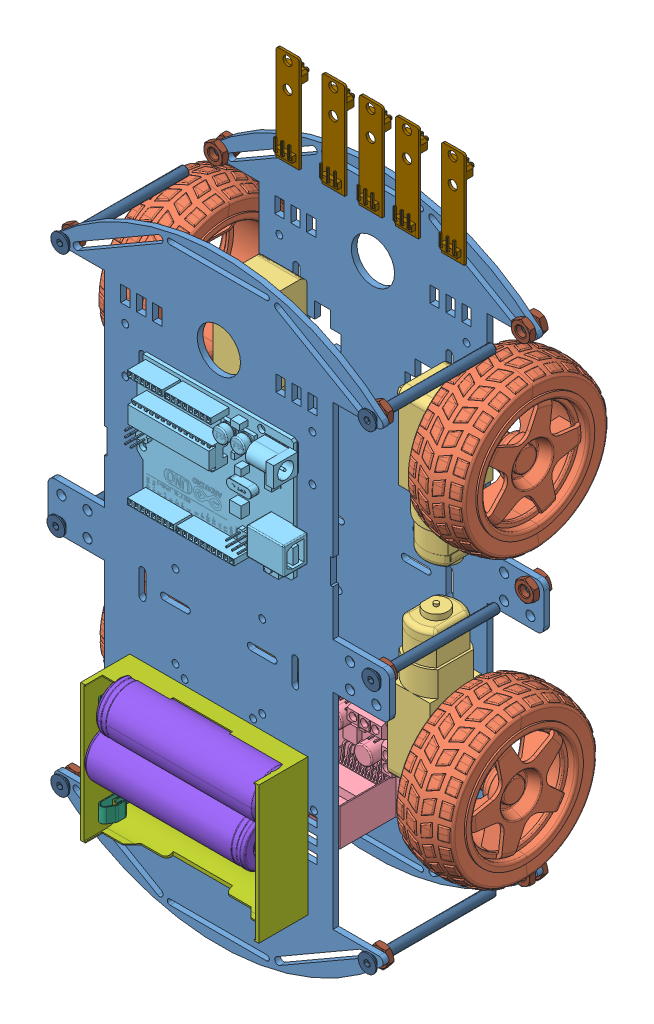
SolidWorks assembly Assem1, configuration Default. Lengths in mm.
Overall size (160.5 287.1 118.28).
55 component instances, 11 part files, 95 mates.
Components (placement in the parent):
- Chassis-1: Chassis [Défaut] at (34.1523 63.1715 225.3046) size (149.66 262 2.5)
- ensemble roue-1: ensemble roue [Default] at (48.6677 124.5638 247.2809) x (0 0.999098 -0.042468) z (-1 0 0) size (89.53 69.08 58.2)
  - Wheel D65x25-1: Wheel D65x25 [Default] at (-64.7956 10.9879 41.7655) size (69.1 69.08 30)
  - Arduino Gear Motor-1: Arduino Gear Motor [Default] at (-75.7856 11.455 2.1655) x (0 0 1) z (-0.999098 0.042468 0) size (37.2 22.5 65.5)
- ensemble roue-2: ensemble roue [Default] at (120.1368 124.5638 230.8284) x (0 0.999098 0.042468) z (1 0 0) size (89.53 69.08 58.2)
  - Wheel D65x25-1: Wheel D65x25 [Default] at (-64.7956 10.9879 41.7655) size (69.1 69.08 30)
  - Arduino Gear Motor-1: Arduino Gear Motor [Default] at (-75.7856 11.455 2.1655) x (0 0 1) z (-0.999098 0.042468 0) size (37.2 22.5 65.5)
- ensemble roue-4: ensemble roue [Default] at (48.1677 122.1564 230.8284) x (0 -0.999098 0.042468) z (-1 0 0) size (89.53 69.08 58.2)
  - Wheel D65x25-1: Wheel D65x25 [Default] at (-64.7956 10.9879 41.7655) size (69.1 69.08 30)
  - Arduino Gear Motor-1: Arduino Gear Motor [Default] at (-75.7856 11.455 2.1655) x (0 0 1) z (-0.999098 0.042468 0) size (37.2 22.5 65.5)
- ensemble roue-5: ensemble roue [Default] at (125.1368 122.1564 247.2809) x (0 -0.999098 -0.042468) z (1 0 0) size (89.53 69.08 58.2)
  - Wheel D65x25-1: Wheel D65x25 [Default] at (-64.7956 10.9879 41.7655) size (69.1 69.08 30)
  - Arduino Gear Motor-1: Arduino Gear Motor [Default] at (-75.7856 11.455 2.1655) x (0 0 1) z (-0.999098 0.042468 0) size (37.2 22.5 65.5)
- L298N Motor Driver-1: L298N Motor Driver [Default] at (84.1523 35.5001 227.8046) x (1 0 0) z (0 -1 0) size (43.5 26 43.5)
- Chassis-2: Chassis [Défaut] at (34.1523 63.1715 292.8046) size (149.66 262 2.5)
- Arduino UNO-1: Arduino UNO [Predeterminado] at (82.8616 175.6554 295.3046) x (-1 0 0) z (0 1 0) size (74.8 15.1 53.3)
- Hold_18650-3p.stp-1: Hold_18650-3p.stp [Default] at (84.1523 53.3601 295.3046) x (0 -1 0) z (0 0 1) size (60 78 25.5)
  - eBom-prt0.stp-1: eBom-prt0.stp [Default] at (-20 -36 0) size (6.4 5.3 21.4)
  - eBom-prt0.stp-2: eBom-prt0.stp [Default] at (-20 36 0) x (-1 0 0) z (0 0 1) size (6.4 5.3 21.4)
  - eBom-prt0.stp-3: eBom-prt0.stp [Default] at (0 -36 0) size (6.4 5.3 21.4)
  - eBom-prt0.stp-4: eBom-prt0.stp [Default] at (0 36 0) x (-1 0 0) z (0 0 1) size (6.4 5.3 21.4)
  - eBom-prt0.stp-5: eBom-prt0.stp [Default] at (20 -36 0) size (6.4 5.3 21.4)
  - eBom-prt0.stp-6: eBom-prt0.stp [Default] at (20 36 0) x (-1 0 0) z (0 0 1) size (6.4 5.3 21.4)
  - eBom-prt1.stp-1: eBom-prt1.stp [Default] at origin size (60 78 21.5)
- 21700_li_battery-1: 21700_li_battery [Default] at (121.6523 73.3601 306.8046) x (0 1 0) z (0 0 1) size (21 70.03 21)
- 21700_li_battery-2: 21700_li_battery [Default] at (46.6523 53.3601 306.8046) x (0 0.381849 -0.924225) z (0 -0.924225 -0.381849) size (21 70.03 21)
- Sensor-1: Sensor [Default] at (120.0976 257.9627 228.8046) x (0 1 0) z (-1 0 0) size (42 9.8 10)
- Sensor-2: Sensor [Default] at (47.7712 257.9627 228.8046) x (0 1 0) z (-1 0 0) size (42 9.8 10)
- socket countersunk head screw_am-14: socket countersunk head screw_am [B18.3.5M - 4 x 0.7 x 55 Socket FCHS  -- 20N] at (151.4798 226.3601 297.7261) x (0 0 -1) z (-0.801739 -0.597675 0) size (55 7.8 7.8)
- socket countersunk head screw_am-15: socket countersunk head screw_am [B18.3.5M - 4 x 0.7 x 55 Socket FCHS  -- 20N] at (16.8248 226.3601 297.7261) x (0 0 -1) z (1 0 0) size (55 7.8 7.8)
- socket countersunk head screw_am-16: socket countersunk head screw_am [B18.3.5M - 4 x 0.7 x 55 Socket FCHS  -- 20N] at (153.1319 128.6487 297.7261) x (0 0 -1) z (1 0 0) size (55 7.8 7.8)
- socket countersunk head screw_am-13: socket countersunk head screw_am [B18.3.5M - 4 x 0.7 x 55 Socket FCHS  -- 20N] at (151.4798 20.3601 297.7261) x (0 0 -1) z (1 0 0) size (55 7.8 7.8)
- socket countersunk head screw_am-17: socket countersunk head screw_am [B18.3.5M - 4 x 0.7 x 55 Socket FCHS  -- 20N] at (16.8248 20.3601 297.7261) x (0 0 -1) z (1 0 0) size (55 7.8 7.8)
- socket countersunk head screw_am-12: socket countersunk head screw_am [B18.3.5M - 4 x 0.7 x 55 Socket FCHS  -- 20N] at (15.1726 118.0715 297.7261) x (0 0 -1) z (1 0 0) size (55 7.8 7.8)
- hex nut jam_am-1: hex nut jam_am [B18.2.4.5M - Hex jam nut,  M5 x 0.8 --D-N] at (151.4798 226.3601 292.8046) size (8 9.24 2.7)
- hex nut jam_am-2: hex nut jam_am [B18.2.4.5M - Hex jam nut,  M5 x 0.8 --D-N] at (151.4798 226.3601 230.5046) size (8 9.24 2.7)
- hex nut jam_am-3: hex nut jam_am [B18.2.4.5M - Hex jam nut,  M5 x 0.8 --D-N] at (151.4798 226.3601 222.6046) x (0.923728 0.383049 0) z (0 0 -1) size (8 9.24 2.7)
- hex nut jam_am-4: hex nut jam_am [B18.2.4.5M - Hex jam nut,  M5 x 0.8 --D-N] at (153.1319 128.6487 290.1046) x (0.923728 0.383049 0) z (0 0 -1) size (8 9.24 2.7)
- hex nut jam_am-5: hex nut jam_am [B18.2.4.5M - Hex jam nut,  M5 x 0.8 --D-N] at (151.4798 20.3601 290.1046) x (0.923728 0.383049 0) z (0 0 -1) size (8 9.24 2.7)
- hex nut jam_am-6: hex nut jam_am [B18.2.4.5M - Hex jam nut,  M5 x 0.8 --D-N] at (16.8248 20.3601 290.1046) x (0.923728 0.383049 0) z (0 0 -1) size (8 9.24 2.7)
- hex nut jam_am-7: hex nut jam_am [B18.2.4.5M - Hex jam nut,  M5 x 0.8 --D-N] at (15.1726 118.0715 290.1046) x (0.923728 0.383049 0) z (0 0 -1) size (8 9.24 2.7)
- hex nut jam_am-8: hex nut jam_am [B18.2.4.5M - Hex jam nut,  M5 x 0.8 --D-N] at (16.8248 226.3601 292.8046) x (0.999998 0.001761 0) z (0 0 1) size (8 9.24 2.7)
- hex nut jam_am-9: hex nut jam_am [B18.2.4.5M - Hex jam nut,  M5 x 0.8 --D-N] at (16.8248 226.3601 230.5046) size (8 9.24 2.7)
- hex nut jam_am-10: hex nut jam_am [B18.2.4.5M - Hex jam nut,  M5 x 0.8 --D-N] at (15.1726 118.0715 230.5046) size (8 9.24 2.7)
- hex nut jam_am-11: hex nut jam_am [B18.2.4.5M - Hex jam nut,  M5 x 0.8 --D-N] at (16.8248 20.3601 230.5046) size (8 9.24 2.7)
- hex nut jam_am-12: hex nut jam_am [B18.2.4.5M - Hex jam nut,  M5 x 0.8 --D-N] at (16.8248 20.3601 222.6046) x (0.923728 0.383049 0) z (0 0 -1) size (8 9.24 2.7)
- hex nut jam_am-13: hex nut jam_am [B18.2.4.5M - Hex jam nut,  M5 x 0.8 --D-N] at (15.1726 118.0715 222.6046) x (0.923728 0.383049 0) z (0 0 -1) size (8 9.24 2.7)
- hex nut jam_am-14: hex nut jam_am [B18.2.4.5M - Hex jam nut,  M5 x 0.8 --D-N] at (16.8248 226.3601 222.6046) x (0.923728 0.383049 0) z (0 0 -1) size (8 9.24 2.7)
- hex nut jam_am-15: hex nut jam_am [B18.2.4.5M - Hex jam nut,  M5 x 0.8 --D-N] at (153.1319 128.6487 222.6046) x (0.923728 0.383049 0) z (0 0 -1) size (8 9.24 2.7)
- hex nut jam_am-16: hex nut jam_am [B18.2.4.5M - Hex jam nut,  M5 x 0.8 --D-N] at (151.4798 20.3601 222.6046) x (0.923728 0.383049 0) z (0 0 -1) size (8 9.24 2.7)
- hex nut jam_am-17: hex nut jam_am [B18.2.4.5M - Hex jam nut,  M5 x 0.8 --D-N] at (151.4798 20.3601 230.5046) size (8 9.24 2.7)
- hex nut jam_am-18: hex nut jam_am [B18.2.4.5M - Hex jam nut,  M5 x 0.8 --D-N] at (153.1319 128.6487 230.5046) size (8 9.24 2.7)
- Sensor-3: Sensor [Default] at (100.0976 257.9627 228.8046) x (0 1 0) z (-1 0 0) size (42 9.8 10)
- Sensor-4: Sensor [Default] at (67.7712 257.9627 228.8046) x (0 1 0) z (-1 0 0) size (42 9.8 10)
- Sensor-5: Sensor [Default] at (84.1523 257.9627 228.8046) x (0 1 0) z (-1 0 0) size (42 9.8 10)
Mates (geometry in assembly coordinates):
- Coincident1: coincident anti-aligned: plane of Chassis-1 through (154.1465 21.3601 227.8046) normal (0 0 1); plane of ensemble roue-1/Arduino Gear Motor-1 through (55.8523 48.3601 227.8046) normal (0 0 -1)
- Parallel1: parallel anti-aligned: plane of Chassis-1 through (34.1523 23.3601 227.8046) normal (-1 0 0); plane of ensemble roue-1/Arduino Gear Motor-1 through (55.8523 48.3601 250.3046) normal (1 0 0)
- Distance1: distance = 3 mm aligned: plane of ensemble roue-1/Arduino Gear Motor-1 through (37.1523 48.3601 227.8046) normal (-1 0 0); plane of Chassis-1 through (34.1523 23.3601 227.8046) normal (-1 0 0)
- Distance5: distance = 25 mm anti-aligned: plane of ensemble roue-1/Arduino Gear Motor-1 through (46.5023 48.3601 239.0546) normal (0 -1 0); plane of Chassis-1 through (34.1523 23.3601 227.8046) normal (0 1 0)
- Coincident6: coincident anti-aligned: plane of Chassis-1 through (154.1465 21.3601 227.8046) normal (0 0 1); plane of ensemble roue-4/Arduino Gear Motor-1 through (36.6523 198.3601 227.8046) normal (0 0 -1)
- Distance3: distance = 2.5 mm aligned: plane of ensemble roue-4/Arduino Gear Motor-1 through (36.6523 198.3601 250.3046) normal (-1 0 0); plane of Chassis-1 through (34.1523 133.3601 227.8046) normal (-1 0 0)
- Distance4: distance = 25 mm anti-aligned: plane of ensemble roue-4/Arduino Gear Motor-1 through (46.0023 198.3601 239.0546) normal (0 1 0); plane of Chassis-1 through (34.1523 223.3601 227.8046) normal (0 -1 0)
- Coincident9: coincident anti-aligned: plane of Chassis-1 through (154.1465 21.3601 227.8046) normal (0 0 1); plane of ensemble roue-2/Arduino Gear Motor-1 through (131.6523 48.3601 227.8046) normal (0 0 -1)
- Distance7: distance = 2.5 mm aligned: plane of Chassis-1 through (134.1523 23.3601 227.8046) normal (1 0 0); plane of ensemble roue-2/Arduino Gear Motor-1 through (131.6523 48.3601 250.3046) normal (1 0 0)
- Distance6: distance = 25 mm anti-aligned: plane of ensemble roue-2/Arduino Gear Motor-1 through (122.3023 48.3601 239.0546) normal (0 -1 0); plane of Chassis-1 through (134.1523 23.3601 227.8046) normal (0 1 0)
- Coincident13: coincident anti-aligned: plane of Chassis-1 through (154.1465 21.3601 227.8046) normal (0 0 1); plane of ensemble roue-5/Arduino Gear Motor-1 through (117.9523 198.3601 227.8046) normal (0 0 -1)
- Distance8: distance = 2.5 mm aligned: plane of ensemble roue-5/Arduino Gear Motor-1 through (136.6523 198.3601 227.8046) normal (1 0 0); plane of Chassis-1 through (134.1523 133.3601 227.8046) normal (1 0 0)
- Distance9: distance = 25 mm anti-aligned: plane of ensemble roue-5/Arduino Gear Motor-1 through (127.3023 198.3601 239.0546) normal (0 1 0); plane of Chassis-1 through (134.1523 223.3601 227.8046) normal (0 -1 0)
- Coincident16: coincident anti-aligned: plane of Chassis-1 through (154.1465 21.3601 227.8046) normal (0 0 1); plane of L298N Motor Driver-1 through (84.1523 35.5001 227.8046) normal (0 0 -1)
- Width1: width anti-aligned: plane of L298N Motor Driver-1 through (62.4023 13.7501 229.3046) normal (-1 0 0); plane of Chassis-1 through (105.9023 13.7501 229.3046) normal (1 0 0); plane of L298N Motor Driver-1 through (134.1523 23.3601 227.8046) normal (1 0 0); plane of Chassis-1 through (34.1523 23.3601 227.8046) normal (-1 0 0)
- Distance10: distance = 56.11 mm anti-aligned: plane of Chassis-1 through (34.1523 113.3601 227.8046) normal (0 -1 0); plane of L298N Motor Driver-1 through (62.4023 57.2501 229.3046) normal (0 1 0)
- Concentric1: concentric aligned: cylinder of Chassis-1 through (15.1726 118.0715 225.3046) axis (0 0 1) radius 2; cylinder of Chassis-2 through (15.1726 118.0715 292.8046) axis (0 0 1) radius 2
- Concentric2: concentric aligned: cylinder of Chassis-1 through (153.1319 128.6487 225.3046) axis (0 0 1) radius 2; cylinder of Chassis-2 through (153.1319 128.6487 292.8046) axis (0 0 1) radius 2
- Distance11: distance = 65 mm anti-aligned: plane of Chassis-1 through (154.1465 21.3601 227.8046) normal (0 0 1); plane of Chassis-2 through (154.1465 21.3601 292.8046) normal (0 0 -1)
- Coincident19: coincident anti-aligned: plane of Chassis-2 through (154.1465 21.3601 295.3046) normal (0 0 1); plane of Arduino UNO-1 through (82.8616 175.6554 295.3046) normal (0 0 -1)
- Width2: width aligned: plane of Arduino UNO-1 through (49.8523 164.0601 296.9046) normal (-1 0 0); plane of Chassis-2 through (118.4523 200.6601 296.9046) normal (1 0 0); plane of Arduino UNO-1 through (34.1523 133.3601 295.3046) normal (-1 0 0); plane of Chassis-2 through (134.1523 133.3601 295.3046) normal (1 0 0)
- Distance12: distance = 15 mm anti-aligned: plane of Arduino UNO-1 through (53.4523 148.3601 296.9046) normal (0 -1 0); plane of Chassis-2 through (134.1523 133.3601 295.3046) normal (0 1 0)
- Coincident21: coincident anti-aligned: plane of Chassis-2 through (154.1465 21.3601 295.3046) normal (0 0 1); plane of Hold_18650-3p.stp-1/eBom-prt1.stp-1 through (84.1523 53.3601 295.3046) normal (0 0 -1)
- Distance13: distance = 30 mm anti-aligned: plane of Hold_18650-3p.stp-1/eBom-prt1.stp-1 through (123.1523 83.3601 295.3046) normal (0 1 0); plane of Chassis-2 through (34.1523 113.3601 295.3046) normal (0 -1 0)
- Width3: width anti-aligned: plane of Hold_18650-3p.stp-1/eBom-prt1.stp-1 through (45.1523 83.3601 295.3046) normal (-1 0 0); plane of Chassis-2 through (123.1523 23.3601 295.3046) normal (1 0 0); plane of Hold_18650-3p.stp-1/eBom-prt1.stp-1 through (134.1523 23.3601 295.3046) normal (1 0 0); plane of Chassis-2 through (34.1523 23.3601 295.3046) normal (-1 0 0)
- Coincident23: coincident anti-aligned: plane of Hold_18650-3p.stp-1/eBom-prt1.stp-1 through (121.6523 53.3601 295.3046) normal (-1 0 0); plane of 21700_li_battery-1 through (121.6523 73.3601 306.8046) normal (1 0 0)
- Concentric3: concentric aligned: cylinder of Hold_18650-3p.stp-1/eBom-prt1.stp-1 through (46.6523 73.3601 306.8046) axis (1 0 0) radius 9.5; cylinder of 21700_li_battery-1 through (51.6523 73.3601 306.8046) axis (1 0 0) radius 10.5
- Coincident24: coincident anti-aligned: plane of Hold_18650-3p.stp-1/eBom-prt1.stp-1 through (46.6523 53.3601 295.3046) normal (1 0 0); plane of 21700_li_battery-2 through (46.6523 53.3601 306.8046) normal (-1 0 0)
- Concentric4: concentric anti-aligned: cylinder of Hold_18650-3p.stp-1/eBom-prt1.stp-1 through (46.6523 53.3601 306.8046) axis (1 0 0) radius 9.5; cylinder of 21700_li_battery-2 through (116.6523 53.3601 306.8046) axis (-1 0 0) radius 10.5
- Coincident26: coincident: plane of Chassis-1 through (154.1465 21.3601 227.8046) normal (0 0 1); plane of Sensor-1 through (121.8755 257.9627 227.8046) normal (0 0 -1)
- Coincident30: coincident: plane of Chassis-1 through (154.1465 21.3601 227.8046) normal (0 0 1); plane of Sensor-2 through (50.876 257.9627 227.8046) normal (0 0 -1)
- Concentric13: concentric aligned: cylinder of Chassis-2 through (151.4798 226.3601 295.3046) axis (0 0 -1) radius 2; cone of socket countersunk head screw_am-6 through (151.4798 226.3601 297.1461) axis (0 0 -1)
- Coincident38: coincident aligned: plane of Chassis-2 through (154.1465 21.3601 295.3046) normal (0 0 1); circle of socket countersunk head screw_am-6
- Concentric14: concentric anti-aligned: cylinder of Chassis-2 through (16.8248 226.3601 295.3046) axis (0 0 -1) radius 2; cylinder of socket countersunk head screw_am-7 through (16.8248 226.3601 297.7261) axis (0 0 1) radius 2
- Coincident39: coincident aligned: plane of Chassis-2 through (154.1465 21.3601 295.3046) normal (0 0 1); circle of socket countersunk head screw_am-7
- Concentric16: concentric aligned: cylinder of Chassis-2 through (15.1726 118.0715 292.8046) axis (0 0 1) radius 2; cylinder of socket countersunk head screw_am-12 through (15.1726 118.0715 297.7261) axis (0 0 1) radius 2
- Concentric17: concentric anti-aligned: cylinder of Chassis-2 through (16.8248 20.3601 295.3046) axis (0 0 -1) radius 2; cylinder of socket countersunk head screw_am-10 through (16.8248 20.3601 297.7261) axis (0 0 1) radius 2
- Concentric18: concentric anti-aligned: cylinder of Chassis-2 through (151.4798 20.3601 295.3046) axis (0 0 -1) radius 2; cylinder of socket countersunk head screw_am-9 through (151.4798 20.3601 297.7261) axis (0 0 1) radius 2
- Concentric19: concentric aligned: cylinder of Chassis-2 through (153.1319 128.6487 292.8046) axis (0 0 1) radius 2; cylinder of socket countersunk head screw_am-8 through (153.1319 128.6487 297.7261) axis (0 0 1) radius 2
- Coincident40: coincident aligned: plane of Chassis-2 through (154.1465 21.3601 295.3046) normal (0 0 1); circle of socket countersunk head screw_am-8
- Coincident41: coincident aligned: plane of Chassis-2 through (154.1465 21.3601 295.3046) normal (0 0 1); circle of socket countersunk head screw_am-9
- Coincident42: coincident aligned: plane of Chassis-2 through (154.1465 21.3601 295.3046) normal (0 0 1); circle of socket countersunk head screw_am-10
- Coincident43: coincident aligned: plane of Chassis-2 through (154.1465 21.3601 295.3046) normal (0 0 1); circle of socket countersunk head screw_am-12
- Concentric22: concentric aligned: cylinder of socket countersunk head screw_am-6 through (151.4798 226.3601 297.7261) axis (0 0 1) radius 2; cylinder of hex nut jam_am-1 through (151.4798 226.3601 267.7671) axis (0 0 1) radius 2.5
- Concentric23: concentric anti-aligned: cylinder of Chassis-1 through (151.4798 226.3601 227.8046) axis (0 0 -1) radius 2; cylinder of hex nut jam_am-2 through (151.4798 226.3601 205.4671) axis (0 0 1) radius 2.5
- Coincident44: coincident anti-aligned: plane of Chassis-1 through (154.1465 21.3601 227.8046) normal (0 0 1); plane of hex nut jam_am-2 through (151.4798 230.9789 227.8046) normal (0 0 -1)
- Concentric24: concentric aligned: cylinder of Chassis-1 through (151.4798 226.3601 227.8046) axis (0 0 -1) radius 2; cylinder of hex nut jam_am-3 through (151.4798 226.3601 247.6421) axis (0 0 -1) radius 2.5
- Coincident45: coincident anti-aligned: plane of Chassis-1 through (154.1465 21.3601 225.3046) normal (0 0 -1); plane of hex nut jam_am-3 through (153.249 222.0936 225.3046) normal (0 0 1)
- Concentric25: concentric anti-aligned: cylinder of socket countersunk head screw_am-8 through (153.1319 128.6487 297.7261) axis (0 0 1) radius 2; cylinder of hex nut jam_am-4 through (153.1319 128.6487 315.1421) axis (0 0 -1) radius 2.5
- Coincident46: coincident anti-aligned: plane of Chassis-2 through (154.1465 21.3601 292.8046) normal (0 0 -1); plane of hex nut jam_am-4 through (154.9011 124.3822 292.8046) normal (0 0 1)
- Concentric26: concentric anti-aligned: cylinder of socket countersunk head screw_am-9 through (151.4798 20.3601 297.7261) axis (0 0 1) radius 2; cylinder of hex nut jam_am-5 through (151.4798 20.3601 315.1421) axis (0 0 -1) radius 2.5
- Coincident47: coincident anti-aligned: plane of Chassis-2 through (154.1465 21.3601 292.8046) normal (0 0 -1); plane of hex nut jam_am-5 through (153.249 16.0936 292.8046) normal (0 0 1)
- Concentric27: concentric anti-aligned: cylinder of socket countersunk head screw_am-10 through (16.8248 20.3601 297.7261) axis (0 0 1) radius 2; cylinder of hex nut jam_am-6 through (16.8248 20.3601 315.1421) axis (0 0 -1) radius 2.5
- Coincident48: coincident anti-aligned: plane of Chassis-2 through (154.1465 21.3601 292.8046) normal (0 0 -1); plane of hex nut jam_am-6 through (18.594 16.0936 292.8046) normal (0 0 1)
- Concentric28: concentric anti-aligned: cylinder of socket countersunk head screw_am-12 through (15.1726 118.0715 297.7261) axis (0 0 1) radius 2; cylinder of hex nut jam_am-7 through (15.1726 118.0715 315.1421) axis (0 0 -1) radius 2.5
- Coincident49: coincident anti-aligned: plane of Chassis-2 through (154.1465 21.3601 292.8046) normal (0 0 -1); plane of hex nut jam_am-7 through (16.9419 113.805 292.8046) normal (0 0 1)
- Concentric29: concentric aligned: cylinder of socket countersunk head screw_am-7 through (16.8248 226.3601 297.7261) axis (0 0 1) radius 2; cylinder of hex nut jam_am-8 through (16.8248 226.3601 267.7671) axis (0 0 1) radius 2.5
- Concentric30: concentric aligned: cylinder of socket countersunk head screw_am-7 through (16.8248 226.3601 297.7261) axis (0 0 1) radius 2; cylinder of hex nut jam_am-9 through (16.8248 226.3601 205.4671) axis (0 0 1) radius 2.5
- Coincident50: coincident anti-aligned: plane of Chassis-1 through (154.1465 21.3601 227.8046) normal (0 0 1); plane of hex nut jam_am-9 through (16.8248 230.9789 227.8046) normal (0 0 -1)
- Concentric31: concentric aligned: cylinder of socket countersunk head screw_am-12 through (15.1726 118.0715 297.7261) axis (0 0 1) radius 2; cylinder of hex nut jam_am-10 through (15.1726 118.0715 205.4671) axis (0 0 1) radius 2.5
- Coincident51: coincident anti-aligned: plane of Chassis-1 through (154.1465 21.3601 227.8046) normal (0 0 1); plane of hex nut jam_am-10 through (15.1726 122.6903 227.8046) normal (0 0 -1)
- Concentric32: concentric aligned: cylinder of socket countersunk head screw_am-10 through (16.8248 20.3601 297.7261) axis (0 0 1) radius 2; cylinder of hex nut jam_am-11 through (16.8248 20.3601 205.4671) axis (0 0 1) radius 2.5
- Coincident52: coincident anti-aligned: plane of Chassis-1 through (154.1465 21.3601 227.8046) normal (0 0 1); plane of hex nut jam_am-11 through (16.8248 24.9789 227.8046) normal (0 0 -1)
- Concentric33: concentric anti-aligned: cylinder of socket countersunk head screw_am-10 through (16.8248 20.3601 297.7261) axis (0 0 1) radius 2; cylinder of hex nut jam_am-12 through (16.8248 20.3601 247.6421) axis (0 0 -1) radius 2.5
- Coincident53: coincident anti-aligned: plane of Chassis-1 through (154.1465 21.3601 225.3046) normal (0 0 -1); plane of hex nut jam_am-12 through (18.594 16.0936 225.3046) normal (0 0 1)
- Concentric34: concentric anti-aligned: cylinder of socket countersunk head screw_am-12 through (15.1726 118.0715 297.7261) axis (0 0 1) radius 2; cylinder of hex nut jam_am-13 through (15.1726 118.0715 247.6421) axis (0 0 -1) radius 2.5
- Coincident54: coincident anti-aligned: plane of Chassis-1 through (154.1465 21.3601 225.3046) normal (0 0 -1); plane of hex nut jam_am-13 through (16.9419 113.805 225.3046) normal (0 0 1)
- Concentric35: concentric anti-aligned: cylinder of socket countersunk head screw_am-7 through (16.8248 226.3601 297.7261) axis (0 0 1) radius 2; cylinder of hex nut jam_am-14 through (16.8248 226.3601 247.6421) axis (0 0 -1) radius 2.5
- Coincident55: coincident anti-aligned: plane of Chassis-1 through (154.1465 21.3601 225.3046) normal (0 0 -1); plane of hex nut jam_am-14 through (18.594 222.0936 225.3046) normal (0 0 1)
- Concentric36: concentric anti-aligned: cylinder of socket countersunk head screw_am-8 through (153.1319 128.6487 297.7261) axis (0 0 1) radius 2; cylinder of hex nut jam_am-15 through (153.1319 128.6487 247.6421) axis (0 0 -1) radius 2.5
- Coincident56: coincident anti-aligned: plane of Chassis-1 through (154.1465 21.3601 225.3046) normal (0 0 -1); plane of hex nut jam_am-15 through (154.9011 124.3822 225.3046) normal (0 0 1)
- Concentric37: concentric anti-aligned: cylinder of socket countersunk head screw_am-9 through (151.4798 20.3601 297.7261) axis (0 0 1) radius 2; cylinder of hex nut jam_am-16 through (151.4798 20.3601 247.6421) axis (0 0 -1) radius 2.5
- Coincident57: coincident anti-aligned: plane of Chassis-1 through (154.1465 21.3601 225.3046) normal (0 0 -1); plane of hex nut jam_am-16 through (153.249 16.0936 225.3046) normal (0 0 1)
- Concentric38: concentric aligned: cylinder of socket countersunk head screw_am-9 through (151.4798 20.3601 297.7261) axis (0 0 1) radius 2; cylinder of hex nut jam_am-17 through (151.4798 20.3601 205.4671) axis (0 0 1) radius 2.5
- Coincident58: coincident anti-aligned: plane of Chassis-1 through (154.1465 21.3601 227.8046) normal (0 0 1); plane of hex nut jam_am-17 through (151.4798 24.9789 227.8046) normal (0 0 -1)
- Concentric39: concentric aligned: cylinder of socket countersunk head screw_am-8 through (153.1319 128.6487 297.7261) axis (0 0 1) radius 2; cylinder of hex nut jam_am-18 through (153.1319 128.6487 205.4671) axis (0 0 1) radius 2.5
- Coincident59: coincident anti-aligned: plane of Chassis-1 through (154.1465 21.3601 227.8046) normal (0 0 1); plane of hex nut jam_am-18 through (153.1319 133.2676 227.8046) normal (0 0 -1)
- Coincident60: coincident anti-aligned: plane of Chassis-2 through (154.1465 21.3601 292.8046) normal (0 0 -1); plane of hex nut jam_am-1 through (151.4798 230.9789 292.8046) normal (0 0 1)
- Coincident61: coincident anti-aligned: plane of Chassis-2 through (154.1465 21.3601 292.8046) normal (0 0 -1); plane of hex nut jam_am-8 through (16.8166 230.9789 292.8046) normal (0 0 1)
- Coincident62: coincident anti-aligned: plane of Chassis-1 through (154.1465 21.3601 227.8046) normal (0 0 1); plane of Sensor-3 through (100.0976 257.9627 227.8046) normal (0 0 -1)
- Coincident63: coincident anti-aligned: plane of Chassis-1 through (154.1465 21.3601 227.8046) normal (0 0 1); plane of Sensor-5 through (84.1523 257.9627 227.8046) normal (0 0 -1)
- Coincident64: coincident anti-aligned: plane of Chassis-1 through (154.1465 21.3601 227.8046) normal (0 0 1); plane of Sensor-4 through (67.7712 257.9627 227.8046) normal (0 0 -1)
- Parallel6: parallel aligned: plane of Chassis-1 through (105.0976 247.4627 227.8046) normal (0 1 0); plane of Sensor-3 through (100.0976 279.4627 227.8046) normal (0 1 0)
- Parallel7: parallel aligned: plane of Chassis-1 through (105.0976 247.4627 227.8046) normal (0 1 0); plane of Sensor-5 through (84.1523 279.4627 227.8046) normal (0 1 0)
- Parallel8: parallel aligned: plane of Chassis-1 through (105.0976 247.4627 227.8046) normal (0 1 0); plane of Sensor-4 through (67.7712 279.4627 227.8046) normal (0 1 0)
- Distance17: distance = 10 mm anti-aligned: plane of Chassis-1 through (105.0976 247.4627 227.8046) normal (0 1 0); plane of Sensor-3 through (100.0976 237.4627 227.8046) normal (0 -1 0)
- Distance18: distance = 10 mm anti-aligned: plane of Sensor-5 through (84.1523 237.4627 227.8046) normal (0 -1 0); plane of Chassis-1 through (105.0976 247.4627 227.8046) normal (0 1 0)
- Distance19: distance = 10 mm anti-aligned: plane of Chassis-1 through (105.0976 247.4627 227.8046) normal (0 1 0); plane of Sensor-4 through (67.7712 237.4627 227.8046) normal (0 -1 0)
- Width4: width anti-aligned: plane of Sensor-5 through (89.1523 257.9627 227.8046) normal (1 0 0); plane of Chassis-1 through (79.1523 257.9627 227.8046) normal (-1 0 0); plane of Sensor-5 through (34.1523 133.3601 227.8046) normal (-1 0 0); plane of Chassis-1 through (134.1523 133.3601 227.8046) normal (1 0 0)
- Coincident71: coincident: line of Chassis-1 through (105.0976 247.4627 227.8046) axis (0 0 -1); plane of Sensor-3 through (105.0976 257.9627 227.8046) normal (1 0 0)
- Coincident72: coincident: line of Chassis-1 through (62.7712 247.4627 227.8046) axis (0 0 -1); plane of Sensor-4 through (62.7712 257.9627 227.8046) normal (-1 0 0)
- Distance20: distance = 10 mm: plane of Chassis-1 through (105.0976 247.4627 227.8046) normal (0 1 0); plane of Sensor-2 through (47.7712 237.4627 227.8046) normal (0 -1 0)
- Distance21: distance = 10 mm: plane of Chassis-1 through (105.0976 247.4627 227.8046) normal (0 1 0); plane of Sensor-1 through (120.0976 237.4627 227.8046) normal (0 -1 0)
- Distance22: distance = 10 mm: plane of Sensor-3 through (105.0976 257.9627 227.8046) normal (1 0 0); line of Sensor-1 through (115.0976 237.4627 228.8046) axis (0 1 0)
- Distance23: distance = 10 mm anti-aligned: plane of Sensor-4 through (62.7712 257.9627 227.8046) normal (-1 0 0); plane of Sensor-2 through (52.7712 257.9627 227.8046) normal (1 0 0)
